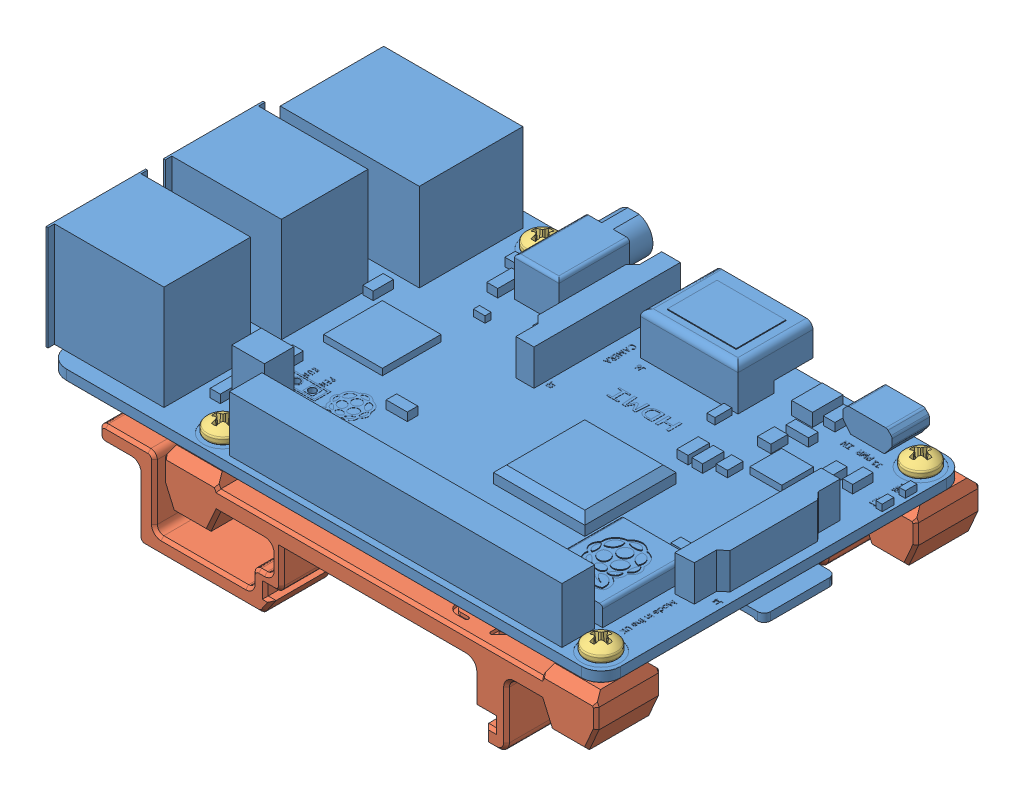
SolidWorks assembly pi_assem, configuration Default. Lengths in mm.
Overall size (89.43 32.12 59.97).
11 component instances, 4 part files, 33 mates.
Components (placement in the parent):
- Ras Pi 3B+-1: Ras Pi 3B+ [Pi] at (32.5 10.5254 -28) x (-1 0 0) z (0 0 -1) size (89.43 19.13 58.47)
- piBracketDIN_v1-1: piBracketDIN_v1 [Default] at (0 0 24.5) x (-1 0 0) z (0 0 -1) size (76.25 14.6 10)
- piBracketDIN_v1-2: piBracketDIN_v1 [Default] at (0 0 -24.5) x (-1 0 0) z (0 0 -1) size (76.25 14.6 10)
- screw M2.5-1: screw M2.5 [6mm] at (29 6.024 -24.5) x (-1 0 0) z (0 1 0) size (5 5 8.1)
- screw M2.5-2: screw M2.5 [6mm] at (29 6.024 24.5) x (-1 0 0) z (0 1 0) size (5 5 8.1)
- screw M2.5-3: screw M2.5 [6mm] at (-29 6.024 24.5) x (-1 0 0) z (0 1 0) size (5 5 8.1)
- screw M2.5-4: screw M2.5 [6mm] at (-29 6.024 -24.5) x (-1 0 0) z (0 1 0) size (5 5 8.1)
- insertM2.5x3.4-1: insertM2.5x3.4 [4mm] at (-29 10.5 -24.5) size (4.37 3.69 4.37)
- insertM2.5x3.4-2: insertM2.5x3.4 [4mm] at (29 10.5 -24.5) size (4.37 3.69 4.37)
- insertM2.5x3.4-3: insertM2.5x3.4 [4mm] at (29 10.5 24.5) size (4.37 3.69 4.37)
- insertM2.5x3.4-4: insertM2.5x3.4 [4mm] at (-29 10.5 24.5) size (4.37 3.69 4.37)
Mates (geometry in assembly coordinates):
- Coincident1: coincident aligned: plane of Ras Pi 3B+-1 through (32.5 10.5254 0) normal (0 0 1)
- Coincident2: coincident anti-aligned: plane of Ras Pi 3B+-1 through (32.5 10.5254 24.5) normal (0 0 1); plane of PiDIN-1 through (0 0 24.5) normal (0 0 -1)
- Concentric1: concentric aligned: line of Ras Pi 3B+-1 through (29 11.9986 24.5) axis (0 -1 0); cylinder of PiDIN-1 through (29 10.5 24.5) axis (0 -1 0) radius 2
- Coincident3: coincident anti-aligned: plane of Ras Pi 3B+-1 through (-49.5 10.5 -25) normal (0 -1 0); plane of PiDIN-1 through (-32.5 10.5 19.5) normal (0 1 0)
- Coincident4: coincident anti-aligned: plane of Ras Pi 3B+-1 through (32.5 10.5254 -24.5) normal (0 0 1); plane of PiDIN-2 through (0 0 -24.5) normal (0 0 -1)
- Concentric2: concentric aligned: line of Ras Pi 3B+-1 through (29 11.9986 -24.5) axis (0 -1 0); cylinder of PiDIN-2 through (29 10.5 -24.5) axis (0 -1 0) radius 2
- Coincident5: coincident anti-aligned: plane of Ras Pi 3B+-1 through (-49.5 10.5 -25) normal (0 -1 0); plane of PiDIN-2 through (32.5 10.5 -29.5) normal (0 1 0)
- Coincident6: coincident aligned: plane of Ras Pi 3B+-1 through (29.5 12.024 25) normal (0 1 0); plane of screw M2.5x6-1 through (29 12.024 -24.5) normal (0 1 0)
- Coincident7: coincident aligned: line of Ras Pi 3B+-1 through (29 11.9986 -24.5) axis (0 -1 0); line of screw M2.5x6-1 through (29 17.625 -24.5) axis (0 -1 0)
- Parallel1: parallel anti-aligned: plane of screw M2.5x6-1 through (29 6.024 -24.5) normal (-1 0 0)
- Coincident9: coincident aligned: plane of Ras Pi 3B+-1 through (29.5 12.024 25) normal (0 1 0); plane of screw M2.5x6-2 through (29 12.024 24.5) normal (0 1 0)
- Coincident10: coincident aligned: line of Ras Pi 3B+-1 through (29 11.9986 24.5) axis (0 -1 0); line of screw M2.5x6-2 through (29 17.625 24.5) axis (0 -1 0)
- Parallel2: parallel anti-aligned: plane of screw M2.5x6-2 through (29 6.024 24.5) normal (-1 0 0)
- Coincident11: coincident aligned: plane of Ras Pi 3B+-1 through (29.5 12.024 25) normal (0 1 0); plane of screw M2.5x6-3 through (-29 12.024 24.5) normal (0 1 0)
- Parallel3: parallel anti-aligned: plane of screw M2.5x6-3 through (-29 6.024 24.5) normal (-1 0 0)
- Coincident12: coincident aligned: line of Ras Pi 3B+-1 through (-29 11.9986 24.5) axis (0 -1 0); line of screw M2.5x6-3 through (-29 17.625 24.5) axis (0 -1 0)
- Coincident13: coincident aligned: plane of Ras Pi 3B+-1 through (29.5 12.024 25) normal (0 1 0); plane of screw M2.5x6-4 through (-29 12.024 -24.5) normal (0 1 0)
- Parallel4: parallel anti-aligned: plane of screw M2.5x6-4 through (-29 6.024 -24.5) normal (-1 0 0)
- Coincident14: coincident aligned: line of Ras Pi 3B+-1 through (-29 11.9986 -24.5) axis (0 -1 0); line of screw M2.5x6-4 through (-29 17.625 -24.5) axis (0 -1 0)
- Coincident15: coincident anti-aligned: plane of PiDIN-1 through (0 0 24.5) normal (-1 0 0)
- Coincident17: coincident aligned: plane of PiDIN-1 through (0 0 24.5) normal (0 1 0)
- Concentric3: concentric anti-aligned: cylinder of PiDIN-2 through (-29 10.5 -24.5) axis (0 -1 0) radius 2; line of insertM2.5x3.4-1 through (-29 5.6207 -24.5) axis (0 1 0)
- Coincident18: coincident aligned: plane of PiDIN-2 through (-32.5 10.5 -29.5) normal (0 1 0); plane of insertM2.5x3.4-1 through (-29 10.5 -24.5) normal (0 1 0)
- Parallel5: parallel aligned: plane of insertM2.5x3.4-1 through (-29 10.5 -24.5) normal (1 0 0)
- Coincident19: coincident aligned: plane of PiDIN-2 through (-32.5 10.5 -29.5) normal (0 1 0); plane of insertM2.5x3.4-2 through (29 10.5 -24.5) normal (0 1 0)
- Parallel6: parallel aligned: plane of insertM2.5x3.4-2 through (29 10.5 -24.5) normal (1 0 0)
- Concentric6: concentric anti-aligned: cylinder of PiDIN-2 through (29 10.5 -24.5) axis (0 -1 0) radius 2; line of insertM2.5x3.4-2 through (29 5.6207 -24.5) axis (0 1 0)
- Coincident20: coincident aligned: plane of PiDIN-2 through (-32.5 10.5 -29.5) normal (0 1 0); plane of insertM2.5x3.4-3 through (29 10.5 24.5) normal (0 1 0)
- Parallel7: parallel aligned: plane of insertM2.5x3.4-3 through (29 10.5 24.5) normal (1 0 0)
- Concentric7: concentric anti-aligned: cylinder of PiDIN-1 through (29 10.5 24.5) axis (0 -1 0) radius 2; line of insertM2.5x3.4-3 through (29 5.6207 24.5) axis (0 1 0)
- Coincident21: coincident aligned: plane of PiDIN-2 through (-32.5 10.5 -29.5) normal (0 1 0); plane of insertM2.5x3.4-4 through (-29 10.5 24.5) normal (0 1 0)
- Parallel8: parallel aligned: plane of insertM2.5x3.4-4 through (-29 10.5 24.5) normal (1 0 0)
- Concentric8: concentric anti-aligned: cylinder of PiDIN-1 through (-29 10.5 24.5) axis (0 -1 0) radius 2; line of insertM2.5x3.4-4 through (-29 5.6207 24.5) axis (0 1 0)
